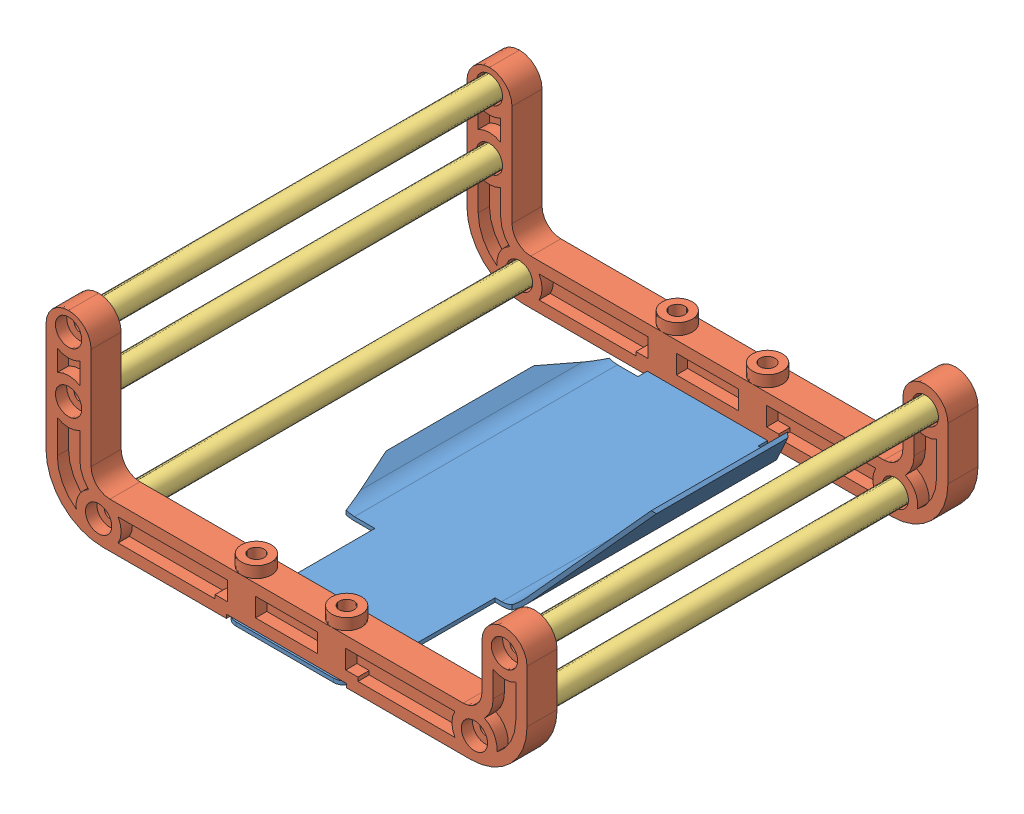
SolidWorks assembly Bumper_mod, configuration Default. Lengths in mm.
Overall size (128 50 121).
8 component instances, 3 part files, 16 mates.
Components (placement in the parent):
- Bumper_3-1: Bumper_3 [Default] at origin size (70.44 25 121)
- Bumper_mod-1: Bumper_mod [Default] at (-24 6 60) x (0 0 -1) z (1 0 0) size (8 50 128)
- Bumper_mod-2: Bumper_mod [Default] at (-24 6 -52) x (0 0 -1) z (1 0 0) size (8 50 128)
- Bumper_2-1: Bumper_2 [Default] at (-50 6 -55) size (6 6 109)
- Bumper_2-2: Bumper_2 [Default] at (-58 29 -55) size (6 6 109)
- Bumper_2-3: Bumper_2 [Default] at (-58 45 -55) size (6 6 109)
- Bumper_2-4: Bumper_2 [Default] at (50 6 -55) size (6 6 109)
- Bumper_2-5: Bumper_2 [Default] at (58 29 -55) x (0.496513 -0.868029 0) z (0 0 1) size (6 6 109)
Mates (geometry in assembly coordinates):
- Concentric1: concentric anti-aligned: cylinder of Bumper_3-1 through (12 1 56) axis (0 -1 0) radius 2; cylinder of Bumper_mod-1 through (12 0 56) axis (0 1 0) radius 2
- Concentric2: concentric anti-aligned: cylinder of Bumper_3-1 through (-12 1 56) axis (0 -1 0) radius 2; cylinder of Bumper_mod-1 through (-12 0 56) axis (0 1 0) radius 2
- Coincident1: coincident anti-aligned: plane of Bumper_3-1 through (-13 1 57.5) normal (0 1 0); plane of Bumper_mod-1 through (-24 1 52) normal (0 -1 0)
- Coincident2: coincident anti-aligned: plane of Bumper_3-1 through (-13 1 57.5) normal (0 1 0); plane of Bumper_mod-2 through (-24 1 -60) normal (0 -1 0)
- Concentric3: concentric anti-aligned: cylinder of Bumper_3-1 through (12 1 -56) axis (0 -1 0) radius 2; cylinder of Bumper_mod-2 through (12 0 -56) axis (0 1 0) radius 2
- Concentric4: concentric anti-aligned: cylinder of Bumper_3-1 through (-12 1 -56) axis (0 -1 0) radius 2; cylinder of Bumper_mod-2 through (-12 0 -56) axis (0 1 0) radius 2
- Concentric5: concentric aligned: cylinder of Bumper_mod-1 through (-50 6 55) axis (0 0 -1) radius 3.5; cylinder of Bumper_2-1 through (-50 6 54) axis (0 0 -1) radius 3
- Concentric6: concentric aligned: cylinder of Bumper_mod-1 through (-58 29 55) axis (0 0 -1) radius 3.5; cylinder of Bumper_2-2 through (-58 29 54) axis (0 0 -1) radius 3
- Concentric7: concentric aligned: cylinder of Bumper_mod-1 through (-58 45 55) axis (0 0 -1) radius 3.5; cylinder of Bumper_2-3 through (-58 45 54) axis (0 0 -1) radius 3
- Coincident3: coincident aligned: circle of Bumper_mod-2; circle of Bumper_2-3
- Coincident4: coincident aligned: circle of Bumper_mod-2; plane of Bumper_2-2 through (-58 29 -55) normal (0 0 -1)
- Coincident5: coincident anti-aligned: plane of Bumper_mod-2 through (-24 6 -55) normal (0 0 1); plane of Bumper_2-1 through (-50 6 -55) normal (0 0 -1)
- Coincident7: coincident aligned: plane of Bumper_2-4 through (50 6 54) normal (0 0 1); plane of Bumper_2-5 through (58 29 54) normal (0 0 1)
- Concentric11: concentric anti-aligned: cylinder of Bumper_mod-2 through (58 29 -55) axis (0 0 1) radius 3.5; cylinder of Bumper_2-5 through (58 29 54) axis (0 0 -1) radius 3
- Concentric12: concentric anti-aligned: cylinder of Bumper_mod-2 through (50 6 -55) axis (0 0 1) radius 3.5; cylinder of Bumper_2-4 through (50 6 54) axis (0 0 -1) radius 3
- Coincident8: coincident anti-aligned: plane of Bumper_mod-2 through (24 6 -55) normal (0 0 1); plane of Bumper_2-5 through (58 29 -55) normal (0 0 -1)
